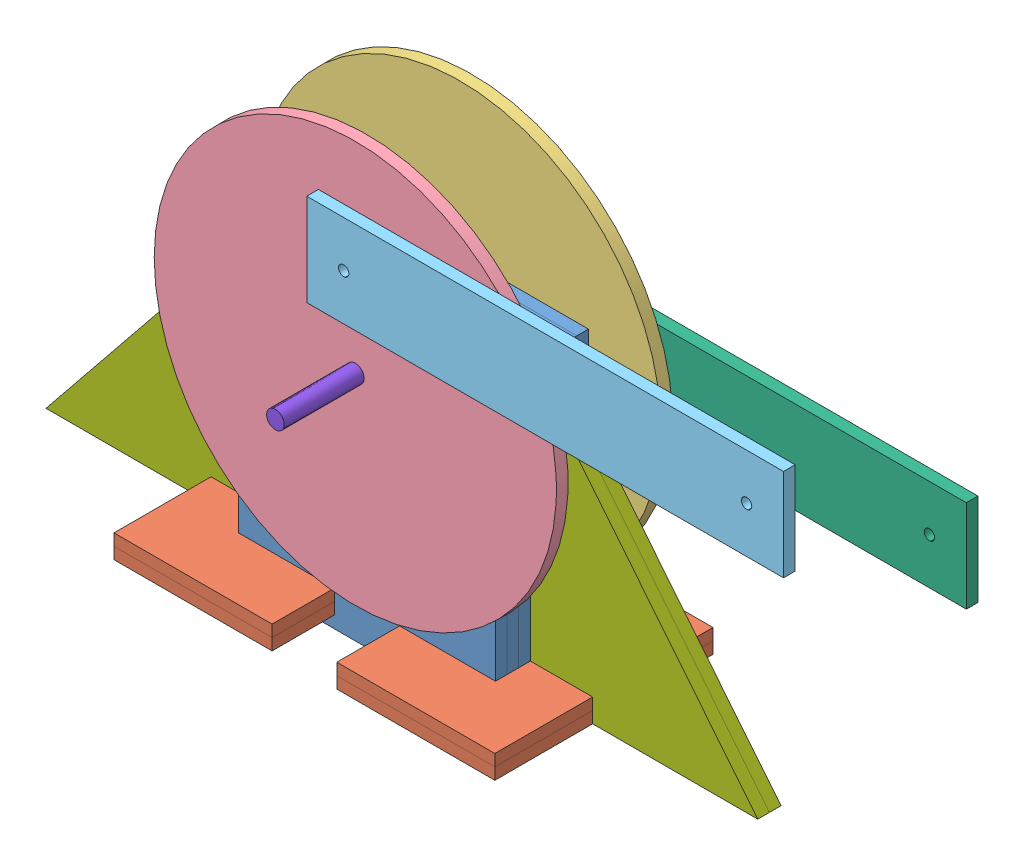
SolidWorks assembly Assembly2, configuration Default. Lengths in mm.
Overall size (232.25 121.35 67.57).
21 component instances, 8 part files, 32 mates.
Components (placement in the parent):
- Stand-1: Stand [Default] at (7.7062 2.6324 70.0462) size (70.17 80.17 3.17)
- Stand-2: Stand [Default] at (7.7062 2.6324 73.2212) size (70.17 80.17 3.17)
- Stand-3: Stand [Default] at (7.7062 2.6324 76.3962) size (70.17 80.17 3.17)
- Stand-4: Stand [Default] at (7.7101 2.6322 79.5712) x (1 0.000058 0) z (0 0 1) size (70.17 80.17 3.17)
- Stand-5: Stand [Default] at (7.7101 2.6322 82.7462) x (1 0.000058 0) z (0 0 1) size (70.17 80.17 3.17)
- Stand-6: Stand [Default] at (7.7062 2.6324 85.9212) size (70.17 80.17 3.17)
- Stand-7: Stand [Default] at (7.7062 2.6324 89.0962) size (70.17 80.17 3.17)
- Stand-8: Stand [Default] at (7.7062 2.6324 92.2712) size (70.17 80.17 3.17)
- StandSupport1-1: StandSupport1 [Default] at (-25.2421 8.979 61.2221) x (0 0 1) z (-1 -0.000058 0) size (59.57 3.17 43.16)
- leftFlyWheel-1: leftFlyWheel [Default] at (9.7564 68.9824 66.8712) size (109.83 109.83 3.17)
- rightFlyWheel-1: rightFlyWheel [Default] at (9.7564 68.9824 95.4462) size (109.83 109.83 3.17)
- rightPistonRod-1: rightPistonRod [Default] at (59.1314 92.9824 98.6212) size (130.17 25.17 3.17)
- leftPistonRod-1: leftPistonRod [Default] at (82.6917 64.9824 63.6962) size (145.17 25.17 3.17)
- StandSupport2-1: StandSupport2 [Default] at (-25.4042 49.0908 79.5712) x (1 0.000058 0) z (0 0 1) size (62.08 76.91 3.17)
- StandSupport2-2: StandSupport2 [Default] at (-25.4042 49.0908 82.7462) x (1 0.000058 0) z (0 0 1) size (62.08 76.91 3.17)
- StandSupport2-3: StandSupport2 [Default] at (44.921 49.0949 82.737) x (-1 -0.000058 0) z (0 0 -1) size (62.08 76.91 3.17)
- StandSupport2-4: StandSupport2 [Default] at (44.921 49.0949 85.912) x (-1 -0.000058 0) z (0 0 -1) size (62.08 76.91 3.17)
- StandSupport1-3: StandSupport1 [Default] at (44.7636 8.9831 104.2704) x (0 0 -1) z (1 0.000058 0) size (59.57 3.17 43.16)
- StandSupport1-4: StandSupport1 [Default] at (-25.2419 5.804 61.2221) x (0 0 1) z (-1 -0.000058 0) size (59.57 3.17 43.16)
- axle-1: axle [Default] at (9.7564 68.9824 92.1979) x (0 0 -1) z (-0.965307 0.261118 0) size (53.57 4.83 4.83)
- StandSupport1-5: StandSupport1 [Default] at (44.7638 5.8081 104.2704) x (0 0 -1) z (1 0.000058 0) size (59.57 3.17 43.16)
Mates (geometry in assembly coordinates):
- Coincident1: coincident aligned: circle of Stand-1; circle of Stand-2
- Coincident2: coincident aligned: circle of Stand-2; circle of Stand-3
- Coincident3: coincident aligned: circle of Stand-3; circle of Stand-4
- Coincident4: coincident aligned: circle of Stand-4; circle of Stand-5
- Coincident5: coincident aligned: circle of Stand-5; circle of Stand-6
- Coincident6: coincident aligned: circle of Stand-6; circle of Stand-7
- Coincident7: coincident aligned: circle of Stand-7; circle of Stand-8
- Coincident10: coincident aligned: circle of Stand-1; circle of leftFlyWheel-1
- Coincident11: coincident aligned: circle of Stand-8; circle of rightFlyWheel-1
- Coincident12: coincident aligned: circle of rightFlyWheel-1; circle of rightPistonRod-1
- Coincident13: coincident aligned: circle of leftFlyWheel-1; circle of leftPistonRod-1
- Coincident14: coincident aligned: line of Stand-4 through (-25.3281 82.7136 82.7462) axis (0 0 -1); line of StandSupport2-1 through (-25.3281 82.7136 82.7462) axis (0 0 -1)
- Coincident17: coincident anti-aligned: plane of Stand-4 through (-25.3235 2.5478 82.7462) normal (-1 -0.000058 0); plane of StandSupport2-1 through (-25.324 12.154 82.7462) normal (1 0.000058 0)
- Coincident18: coincident anti-aligned: line of Stand-5 through (-25.3281 82.7136 82.7462) axis (0.000058 -1 0); line of StandSupport2-1 through (-25.324 12.154 82.7462) axis (-0.000058 1 0)
- Coincident19: coincident aligned: line of Stand-5 through (-25.3281 82.7136 85.9212) axis (0 0 -1); line of StandSupport2-2 through (-25.3281 82.7136 85.9212) axis (0 0 -1)
- Coincident20: coincident aligned: line of StandSupport2-1 through (-25.324 12.154 82.7462) axis (-0.000058 1 0); line of StandSupport2-2 through (-25.324 12.154 82.7462) axis (-0.000058 1 0)
- Coincident30: coincident aligned: point of StandSupport2-4; point of StandSupport2-3
- Coincident31: coincident aligned: line of StandSupport2-3 through (44.841 82.7177 82.737) axis (0.628122 -0.778115 0); line of StandSupport2-4 through (44.841 82.7177 82.737) axis (0.628122 -0.778115 0)
- Coincident32: coincident aligned: line of StandSupport2-3 through (44.8451 12.1581 82.737) axis (-0.000058 1 0); line of StandSupport2-4 through (44.8451 12.1581 82.737) axis (-0.000058 1 0)
- Coincident33: coincident anti-aligned: line of Stand-5 through (44.841 82.7177 85.9212) axis (0 0 -1); line of StandSupport2-4 through (44.841 82.7177 82.737) axis (0 0 1)
- Coincident34: coincident anti-aligned: plane of Stand-5 through (44.841 82.7177 85.9212) normal (1 0.000058 0); plane of StandSupport2-4 through (44.8451 12.1581 82.737) normal (-1 -0.000058 0)
- Coincident36: coincident: plane of StandSupport1-1 through (-42.3235 12.1531 112.4428) normal (-1 -0.000058 0); line of StandSupport2-1 through (-42.3232 5.8015 82.7462) axis (-0.000058 1 0)
- Coincident38: coincident anti-aligned: plane of StandSupport1-1 through (-25.2423 12.154 61.2221) normal (-0.000058 1 0); line of StandSupport2-1 through (-42.3235 12.1531 82.7462) axis (1 0.000058 0)
- Coincident44: coincident aligned: line of StandSupport1-1 through (-42.3233 8.9781 112.4428) axis (1 0.000058 -0.000238); line of StandSupport1-4 through (-42.3233 8.9781 112.4428) axis (1 0.000058 -0.000238)
- Coincident45: coincident anti-aligned: plane of StandSupport1-1 through (-25.2421 8.979 61.2221) normal (0.000058 -1 0); plane of StandSupport1-4 through (-25.2421 8.979 61.2221) normal (-0.000058 1 0)
- Coincident46: coincident aligned: line of StandSupport1-1 through (0.841 8.9806 70.0462) axis (0 0 -1); line of StandSupport1-4 through (0.841 8.9806 70.0462) axis (0 0 -1)
- Coincident49: coincident aligned: circle of leftFlyWheel-1; circle of axle-1
- Coincident50: coincident: plane of StandSupport2-4 through (61.8446 12.1591 82.737) normal (-1 -0.000058 0); line of StandSupport1-3 through (61.8446 12.1591 112.616) axis (0 0 -1)
- Coincident51: coincident anti-aligned: plane of StandSupport2-4 through (61.7502 12.1591 82.737) normal (0.000058 -1 0); plane of StandSupport1-3 through (44.7634 12.1581 104.2704) normal (-0.000058 1 0)
- Coincident52: coincident anti-aligned: plane of Stand-8 through (7.7062 2.6324 95.4462) normal (0 0 1); plane of StandSupport1-3 through (44.5945 12.1581 95.4462) normal (0 0 -1)
- Coincident53: coincident aligned: line of StandSupport1-3 through (61.8448 8.9841 112.616) axis (0 0 -1); line of StandSupport1-5 through (61.8448 8.9841 112.616) axis (0 0 -1)
- Coincident54: coincident aligned: line of StandSupport1-3 through (61.8448 8.9841 53.0497) axis (-1 -0.000058 0.000238); line of StandSupport1-5 through (61.8448 8.9841 53.0497) axis (-1 -0.000058 0.000238)
